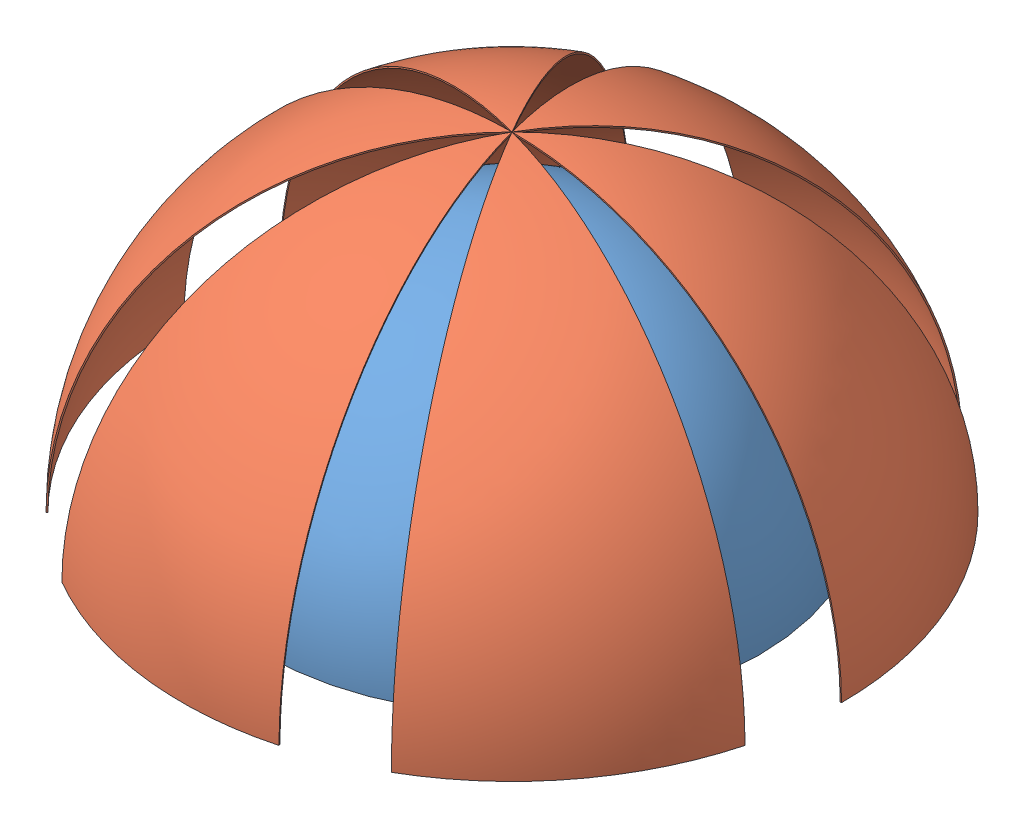
SolidWorks assembly mega_cocoon, configuration Default. Lengths in mm.
Overall size (12332.23 6167.36 12332.23).
2 component instances, 2 part files, 1 mates.
Components (placement in the parent):
- dome_cover_16-1: dome_cover_16 [Default] at (2980.5902 3838.7151 8015.0612) size (9245.6 4622.8 9245.6)
- dome_cover_20-1: dome_cover_20 [Default] at (2980.5902 3838.7151 8015.0612) size (12331.7 6165.85 12331.7)
Mates (geometry in assembly coordinates):
- Coincident3: coincident: point of dome_cover_16-1; point of dome_cover_20-1
